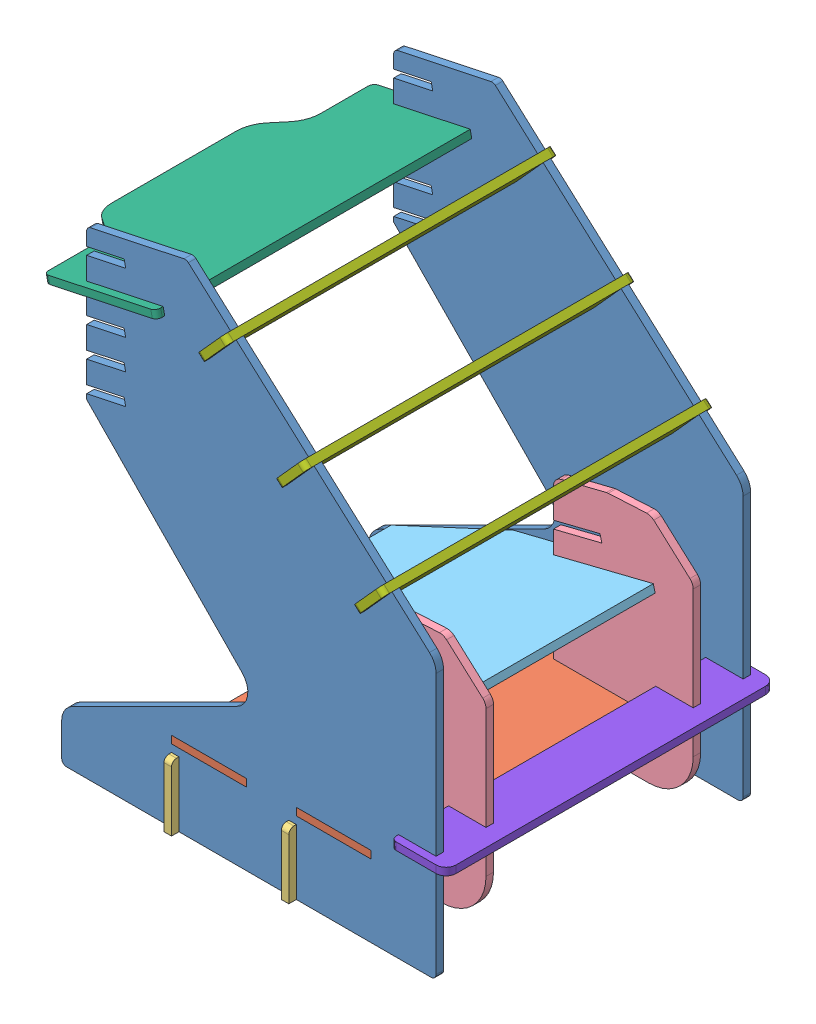
SolidWorks assembly simuladorV3, configuration Default. Lengths in mm.
Overall size (875.06 999.16 660).
13 component instances, 8 part files, 35 mates.
Components (placement in the parent):
- Part13-1: Part13 [Default] at origin size (750 999.16 15)
- Part13-3: Part13 [Default] at (0 0 -615) size (750 999.16 15)
- Part16-1: Part16 [Default] at (0 442.3925 -615) x (1 0 0) z (0 1 0) size (450 630 15)
- Part17-1: Part17 [Default] at (1707.3149 0 -615) x (0 0 1) z (-1 0 0) size (660 130 15)
- Part17-2: Part17 [Default] at (1472.3149 0 -615) x (0 0 1) z (-1 0 0) size (660 130 15)
- Part18-1: Part18 [Default] at origin size (280 466.21 15)
- Part18-2: Part18 [Default] at (0 0 -415) size (280 466.21 15)
- Part19-1: Part19 [Default] at (-46.2035 185.3123 -415) x (0.970296 0.241922 0) z (-0.241922 0.970296 0) size (500 460 15)
- Part20-1: Part20 [Default] at (-177.1855 833.5921 0) x (0.978148 0.207912 0) z (-0.207912 0.978148 0) size (300 660 15)
- Part21-1: Part21 [Default] at (264.9421 -238.4479 0) x (0 0 -1) z (0.743294 -0.668965 0) size (660 80 15)
- Part21-3: Part21 [Default] at (421.0339 -378.9305 0) x (0 0 -1) z (0.743294 -0.668965 0) size (660 80 15)
- Part21-4: Part21 [Default] at (577.1257 -519.4131 0) x (0 0 -1) z (0.743294 -0.668965 0) size (660 80 15)
- Part22-1: Part22 [Default] at (0 497.3925 0) x (1 0 0) z (0 1 0) size (110 660 15)
Mates (geometry in assembly coordinates):
- InPlace3: in place: plane of ? through (0 0 0) normal (0 0 1); moOrthogonalPlaneRef_w of ? through (0 0 0) normal (0 1 0); plane of ? through (0 0 0) normal (1 0 0); unknown of ?
- Coincident7: coincident aligned: 
- Coincident8: coincident aligned: plane of Part13^simulador-1 through (0 0 0) normal (0 1 0)
- Coincident9: coincident anti-aligned: plane of Part13^simulador-1 through (0 0 0) normal (1 0 0)
- InPlace4: in place: plane of Part13-3 through (1707.3149 442.3925 -325) normal (0 1 0); plane of ? through (0 442.3925 0) normal (0 1 0); plane of Part13-3 through (1707.3149 442.3925 -325) normal (0 1 0); plane of ? through (0 442.3925 0) normal (0 0 -1); plane of Part13-3 through (1707.3149 442.3925 -325) normal (0 1 0); plane of ? through (0 442.3925 0) normal (1 0 0); plane of Part13-3 through (1707.3149 442.3925 -325) normal (0 1 0); unknown of Part16-1
- Coincident10: coincident aligned: plane of ?; plane of ?
- Coincident11: coincident aligned: moOrthogonalPlaneRef_w of Part13^simulador-2 through (0 442.3925 -615) normal (0 0 -1); plane of Part16^simulador-1 through (0 442.3925 -615) normal (0 0 -1)
- Coincident12: coincident anti-aligned: moOrthogonalPlaneRef_w of Part13^simulador-2 through (0 442.3925 -615) normal (-1 0 0); plane of Part16^simulador-1 through (0 442.3925 -615) normal (1 0 0)
- InPlace5: in place: plane of Part13-3 through (1857.3149 297.3925 -325) normal (-1 0 0); plane of ? through (1857.3149 0 0) normal (-1 0 0); plane of Part13-3 through (1857.3149 297.3925 -325) normal (-1 0 0); plane of ? through (1857.3149 0 0) normal (0 1 0); plane of Part13-3 through (1857.3149 297.3925 -325) normal (-1 0 0); plane of ? through (1857.3149 0 0) normal (0 0 1); plane of Part13-3 through (1707.3149 297.3925 -325) normal (-1 0 0); unknown of Part17-1
- Coincident13: coincident aligned: plane of ?; plane of ?
- Coincident14: coincident aligned: moOrthogonalPlaneRef_w of Part13^simulador-2 through (1707.3149 0 -615) normal (0 1 0); plane of Part17^simulador-1 through (1707.3149 0 -615) normal (0 1 0)
- Coincident15: coincident anti-aligned: moOrthogonalPlaneRef_w of Part13^simulador-2 through (1707.3149 0 -615) normal (0 0 -1); plane of Part17^simulador-1 through (1707.3149 0 -615) normal (0 0 1)
- Coincident16: coincident anti-aligned: plane of Part13^simulador-1 through (1457.3149 297.3925 290) normal (1 0 0); plane of Part17^simulador-2 through (1457.3149 0 -615) normal (-1 0 0)
- Coincident17: coincident aligned: plane of Part17^simulador-1 through (1692.3149 297.3925 330) normal (0 0 1); plane of Part17^simulador-2 through (1457.3149 297.3925 330) normal (0 0 1)
- Coincident18: coincident aligned: plane of Part13^simulador-1 through (1987.3149 297.3925 315) normal (0 -1 0); plane of Part17^simulador-2 through (1457.3149 297.3925 -330) normal (0 -1 0)
- InPlace6: in place: plane of ? through (0 0 0) normal (0 0 1); plane of ? through (0 0 0) normal (0 1 0); plane of ? through (0 0 0) normal (1 0 0); unknown of ?
- Coincident19: coincident aligned: 
- Coincident20: coincident aligned: plane of Part18^simulador-1 through (0 0 0) normal (0 1 0)
- Coincident21: coincident anti-aligned: plane of Part18^simulador-1 through (0 0 0) normal (1 0 0)
- InPlace7: in place: plane of Part18-2 through (1707.3149 622.5135 -215) normal (-0.241922 0.970296 0); plane of ? through (-46.2035 185.3123 0) normal (-0.241922 0.970296 0); plane of Part18-2 through (1707.3149 622.5135 -215) normal (-0.241922 0.970296 0); plane of ? through (-46.2035 185.3123 0) normal (0 0 -1); plane of Part18-2 through (1707.3149 622.5135 -215) normal (-0.241922 0.970296 0); plane of ? through (-46.2035 185.3123 0) normal (0.970296 0.241922 0); plane of Part18-2 through (1707.3149 622.5135 -215) normal (-0.241922 0.970296 0); unknown of Part19-1
- Coincident22: coincident aligned: plane of ?; plane of ?
- Coincident23: coincident aligned: moOrthogonalPlaneRef_w of Part18^simulador-2 through (-46.2035 185.3123 -415) normal (0 0 -1); plane of Part19^simulador-1 through (-46.2035 185.3123 -415) normal (0 0 -1)
- Coincident24: coincident anti-aligned: moOrthogonalPlaneRef_w of Part18^simulador-2 through (-46.2035 185.3123 -415) normal (-0.970296 -0.241922 0); plane of Part19^simulador-1 through (-46.2035 185.3123 -415) normal (0.970296 0.241922 0)
- InPlace8: in place: plane of ? through (1287.3149 1144.8812 290) normal (-0.207912 0.978148 0); plane of Part20-1 through (-177.1855 833.5921 0) normal (-0.207912 0.978148 0); plane of ? through (1287.3149 1144.8812 290) normal (-0.207912 0.978148 0); plane of Part20-1 through (-177.1855 833.5921 0) normal (0 0 -1); plane of ? through (1287.3149 1144.8812 290) normal (-0.207912 0.978148 0); plane of Part20-1 through (-177.1855 833.5921 0) normal (0.978148 0.207912 0); plane of ? through (1287.3149 1144.8812 290) normal (-0.207912 0.978148 0); unknown of Part20-1
- Coincident25: coincident aligned: plane of ?; plane of ?
- Coincident26: coincident aligned: moOrthogonalPlaneRef_w of Part13^simulador-1 through (-177.1855 833.5921 0) normal (0 0 -1); plane of Part20^simuladorV3-1 through (-177.1855 833.5921 0) normal (0 0 -1)
- Coincident27: coincident anti-aligned: moOrthogonalPlaneRef_w of Part13^simulador-1 through (-177.1855 833.5921 0) normal (-0.978148 -0.207912 0); plane of Part20^simuladorV3-1 through (-177.1855 833.5921 0) normal (0.978148 0.207912 0)
- InPlace9: in place: plane of ? through (1553.3496 1237.9613 290) normal (0.743294 -0.668965 0); plane of ? through (242.6433 -218.379 0) normal (0.743294 -0.668965 0); plane of ? through (1553.3496 1237.9613 290) normal (0.743294 -0.668965 0); plane of ? through (242.6433 -218.379 0) normal (0.668965 0.743294 0); plane of ? through (1553.3496 1237.9613 290) normal (0.743294 -0.668965 0); plane of ? through (242.6433 -218.379 0) normal (0 0 -1); plane of ? through (1575.6484 1217.8924 290) normal (0.743294 -0.668965 0); unknown of Part21-1
- Coincident19: coincident aligned: plane of ?; plane of ?
- Coincident20: coincident aligned: moOrthogonalPlaneRef_w of Part13^simuladorV3-1 through (264.9421 -238.4479 0) normal (0.668965 0.743294 0); plane of Part21^simuladorV3-1 through (264.9421 -238.4479 0) normal (0.668965 0.743294 0)
- Coincident21: coincident anti-aligned: moOrthogonalPlaneRef_w of Part13^simuladorV3-1 through (264.9421 -238.4479 0) normal (0 0 1); plane of Part21^simuladorV3-1 through (264.9421 -238.4479 0) normal (0 0 -1)
- InPlace10: in place: plane of ? through (1987.3149 497.3925 450) normal (0 1 0); plane of Part22-1 through (0 497.3925 0) normal (0 1 0); plane of ? through (1987.3149 497.3925 450) normal (0 1 0); plane of Part22-1 through (0 497.3925 0) normal (0 0 -1); plane of ? through (1987.3149 497.3925 450) normal (0 1 0); plane of Part22-1 through (0 497.3925 0) normal (1 0 0); plane of ? through (1987.3149 497.3925 450) normal (0 1 0); unknown of Part22-1
- Coincident22: coincident aligned: plane of ?; plane of ?
- Coincident23: coincident aligned: moOrthogonalPlaneRef_w of Part13^simuladorV3-1 through (0 497.3925 0) normal (0 0 -1); plane of Part22^simuladorV3-1 through (0 497.3925 0) normal (0 0 -1)
- Coincident24: coincident anti-aligned: moOrthogonalPlaneRef_w of Part13^simuladorV3-1 through (0 497.3925 0) normal (-1 0 0); plane of Part22^simuladorV3-1 through (0 497.3925 0) normal (1 0 0)
